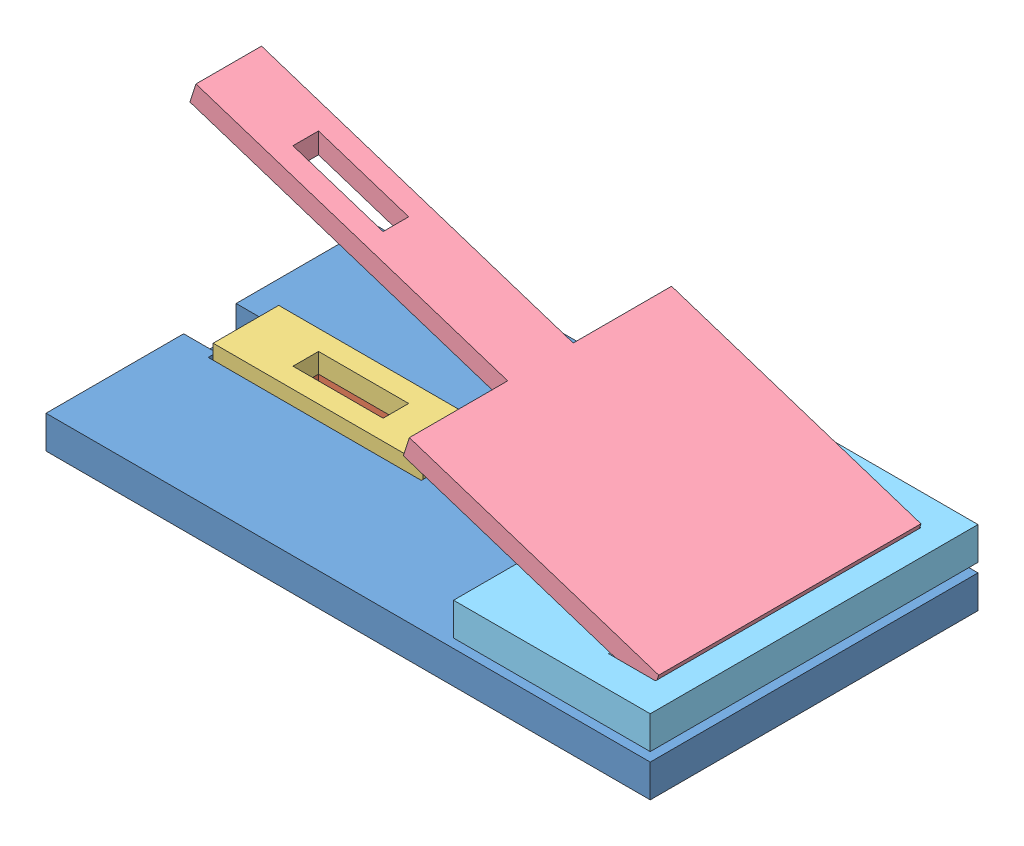
SolidWorks assembly Us_tube_ASM, configuration 預設. Lengths in mm.
Overall size (103.34 39.94 50).
5 component instances, 5 part files, 11 mates.
Components (placement in the parent):
- Base_UsTube-1: Base_UsTube [預設] at origin size (100.72 32 50)
- Heater2_UsTube-1: Heater2_UsTube [預設] at (-24.59 1 0) size (32 3 10)
- Heater1_UsTube-2: Heater1_UsTube [預設] at (-24.59 4 0) size (32 3 10)
- TCooler_UsTube-2: TCooler_UsTube [預設] at (-17.5082 28.4383 0.3158) x (0.951057 -0.309017 0) z (0 0 1) size (90 3 40)
- Base1_UsTube-1: Base1_UsTube [預設] at (1.3115 6.3817 0) size (83.1 32 50)
Mates (geometry in assembly coordinates):
- 重合/共線/共點8: coincident anti-aligned: plane of Base_UsTube-1 through (0 1 0) normal (0 1 0); plane of Heater2_UsTube-1 through (-24.59 1 0) normal (0 -1 0)
- 重合/共線/共點10: coincident anti-aligned: plane of Heater2_UsTube-1 through (-24.59 4 0) normal (0 1 0); plane of Heater1_UsTube-2 through (-24.59 4 0) normal (0 -1 0)
- 重合/共線/共點11: coincident aligned: plane of Heater2_UsTube-1 through (-31.465 3 1.95) normal (0 0 -1); plane of Heater1_UsTube-2 through (-31.465 4 1.95) normal (0 0 -1)
- 重合/共線/共點12: coincident aligned: plane of Heater2_UsTube-1 through (-40.59 4 5) normal (-1 0 0); plane of Heater1_UsTube-2 through (-40.59 7 5) normal (-1 0 0)
- 重合/共線/共點14: coincident: line of Base_UsTube-1 through (87.3738 -28.47 32) axis (0 0.951057 -0.309017); plane of TCooler_UsTube-2 through (-17.5082 28.4383 0.3158) normal (-0.309017 -0.951057 0)
- 重合/共線/共點15: coincident aligned: plane of Heater1_UsTube-2 through (-31.465 4 -1.95) normal (0 0 1); plane of TCooler_UsTube-2 through (-17.5082 28.4383 -1.95) normal (0 0 1)
- 重合/共線/共點16: coincident aligned: plane of Heater1_UsTube-2 through (-31.465 4 1.95) normal (1 0 0); plane of TCooler_UsTube-2 through (-31.465 32.9731 -1.95) normal (1 0 0)
- 重合/共線/共點17: coincident anti-aligned: plane of Base_UsTube-1 through (-8.59 1 -5.25) normal (-1 0 0); plane of Heater2_UsTube-1 through (-8.59 4 5) normal (1 0 0)
- 重合/共線/共點18: coincident anti-aligned: plane of TCooler_UsTube-2 through (-17.5082 28.4383 0.3158) normal (-0.309017 -0.951057 0); plane of Base1_UsTube-1 through (5.9966 20.8011 0) normal (0.309017 0.951057 0)
- 重合/共線/共點19: coincident anti-aligned: plane of TCooler_UsTube-2 through (42.3843 12.1324 -20) normal (0.951057 -0.309017 0); plane of Base1_UsTube-1 through (41.4573 9.2793 20.25) normal (-0.951057 0.309017 0)
- 重合/共線/共點20: coincident aligned: plane of Base_UsTube-1 through (-46.09 5 25) normal (0 0 1); plane of Base1_UsTube-1 through (-43.4635 11.3817 25) normal (0 0 1)
